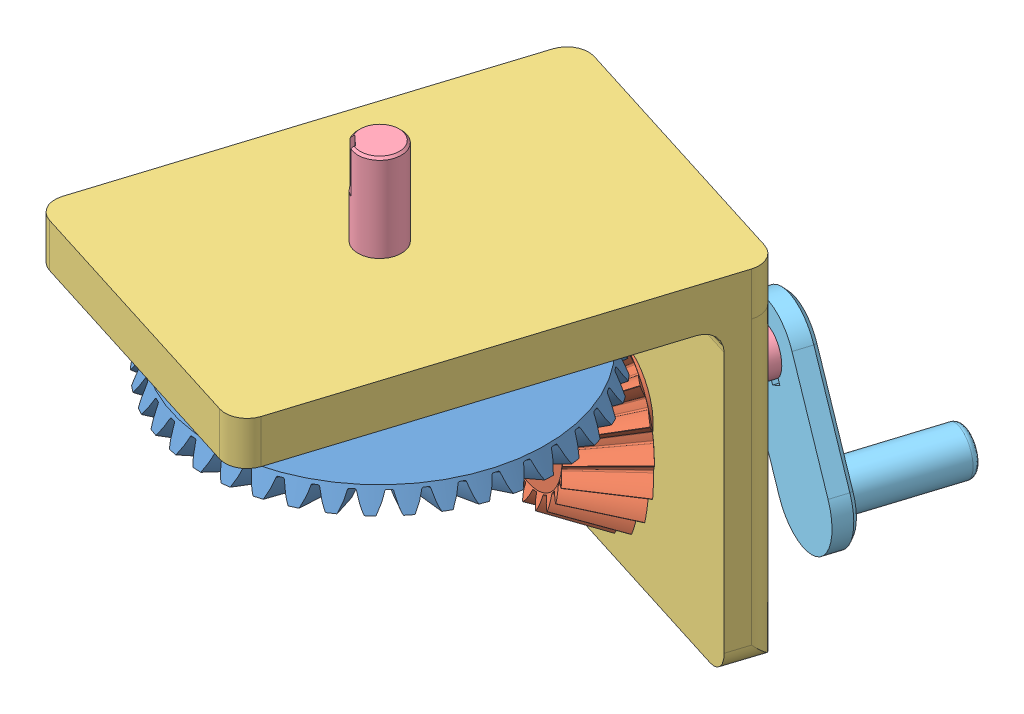
SolidWorks assembly Assem1, configuration Default. Lengths in mm.
Overall size (249.18 200.6 335.24).
6 component instances, 5 part files, 16 mates.
Components (placement in the parent):
- straight bevel gear_am-1: straight bevel gear_am [Metric - Straight bevel gear 4M 40GT 20PT 20PA 30FW ---40O40H70MD20S1] x (0 -1 0) z (-0.734774 0 -0.678313) size (83.14 162.34 204.8)
- straight bevel pinion_am-1: straight bevel pinion_am [Metric - Straight bevel pinion 4M20PT 40GT 20PA 30FW ---20O40H90MD20S1] at (24.5973 -46.8569 -78.1039) x (-0.300386 0 0.953818) z (0.821816 0.507575 0.258815) size (39.95 88.85 88.85)
- TABAN-1: TABAN [Default] at (39.7324 43.1431 106.8706) x (0.300386 0 -0.953818) z (0 1 0) size (200 140 160)
- ŞAFT-1: ŞAFT [Default] at (46.0854 -46.8569 -146.335) x (-0.821816 -0.507575 -0.258815) z (-0.300386 0 0.953818) size (20 20 100)
- ŞAFT-2: ŞAFT [Default] at (0 83.2837 0) x (0.734774 0 0.678313) z (0 -1 0) size (20 20 100)
- Çevirme Kolu-1: Çevirme Kolu [Default] at (42.7811 -46.8569 -135.843) x (0.484134 -0.861608 0.152469) z (0.300386 0 -0.953818) size (90 40 60)
Mates (geometry in assembly coordinates):
- Coincident4: coincident: plane of straight bevel gear_am-1 through (0 0 0) normal (0 1 0); plane of assembly through (0 0 0) normal (0 1 0)
- Concentric1: concentric: cylinder of straight bevel gear_am-1 through (0 -70.0001 0) axis (0 1 0) radius 10; point of assembly
- Coincident5: coincident: point of straight bevel gear_am-1; point of straight bevel pinion_am-1
- Perpendicular1: perpendicular: line of straight bevel gear_am-1 through (0 10 0) axis (0 -1 0); line of straight bevel pinion_am-1 through (27.6012 -46.8569 -87.6421) axis (-0.300386 0 0.953818)
- GearMate1: gear = 40 : 20 mm: circle of straight bevel pinion_am-1; circle of straight bevel gear_am-1
- Concentric2: concentric: cylinder of straight bevel gear_am-1 through (0 -70.0001 0) axis (0 1 0) radius 10; cylinder of TABAN-1 through (0 43.1431 0) axis (0 -1 0) radius 10
- Coincident7: coincident: plane of straight bevel gear_am-1 through (0 23.1432 0) normal (0 1 0); plane of TABAN-1 through (87.2677 23.1431 -77.3586) normal (0 -1 0)
- Concentric3: concentric: cylinder of straight bevel pinion_am-1 through (-2.4375 -46.8569 7.7397) axis (0.300386 0 -0.953818) radius 10; cylinder of TABAN-1 through (33.0425 -46.8569 -104.9199) axis (-0.300386 0 0.953818) radius 10
- Concentric9: concentric: circle of straight bevel pinion_am-1; circle of ŞAFT-1
- Coincident11: coincident: circle of straight bevel pinion_am-1; circle of ŞAFT-1
- Parallel2: parallel: line of straight bevel pinion_am-1 through (20.0786 -59.4082 -50.7319) axis (0.821816 0.507575 0.258815); line of ŞAFT-1 through (22.3853 -52.227 -48.957) axis (-0.821816 -0.507575 -0.258815)
- Concentric12: concentric: cylinder of TABAN-1 through (0 43.1431 0) axis (0 -1 0) radius 10; cylinder of ŞAFT-2 through (0 -16.7163 0) axis (0 1 0) radius 10
- Coincident13: coincident: circle of straight bevel gear_am-1; circle of ŞAFT-2
- Parallel3: parallel: line of straight bevel gear_am-1 through (-6.4781 -15.7163 11.44) axis (-0.734774 0 -0.678313); line of ŞAFT-2 through (-7.6308 -16.7163 3.8433) axis (0.734774 0 0.678313)
- Coincident16: coincident: circle of ŞAFT-1; circle of Çevirme Kolu-1
- Parallel4: parallel: line of ŞAFT-1 through (47.493 -55.2725 -145.8917) axis (0.821816 0.507575 0.258815); line of Çevirme Kolu-1 through (54.0601 -55.6735 -142.7751) axis (-0.821816 -0.507575 -0.258815)
